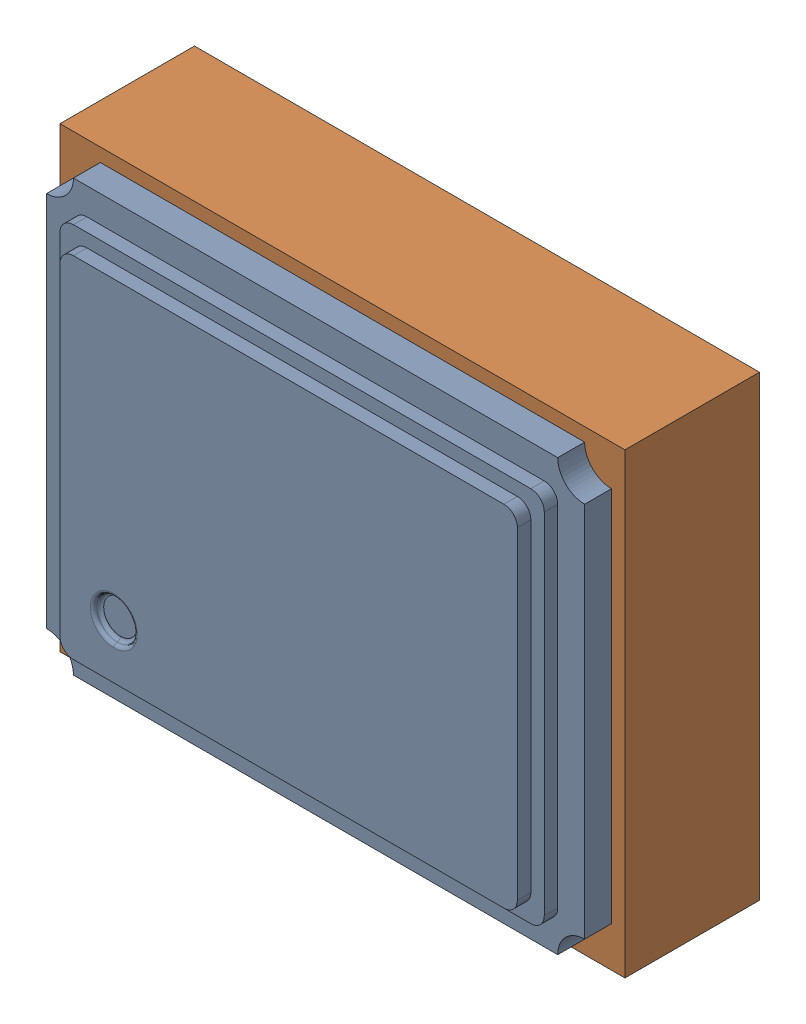
SolidWorks assembly X2, configuration Default. Lengths in mm.
Overall size (9.48 6.01 1.61).
5 component instances, 3 part files, 0 mates.
Components (placement in the parent):
- 1088882936-1: 1088882936 [Default] at (6.6875 4.6125 0.5) size (0.33 0.33 0.01)
  - Extruded-10-1: Extruded-10 [Default] at origin size (0.33 0.33 0.01)
- 1737252136-1: 1737252136 [Default] at (7.425 5.15 0) size (2.1 1.7 0.5)
  - Extruded-11-1: Extruded-11 [Default] at origin size (2.1 1.7 0.5)
- NX2016-1: NX2016 [Default] at (7.4251 5.1501 0) x (1 0 0) z (0 -1 0) size (2.01 0.71 1.61)
